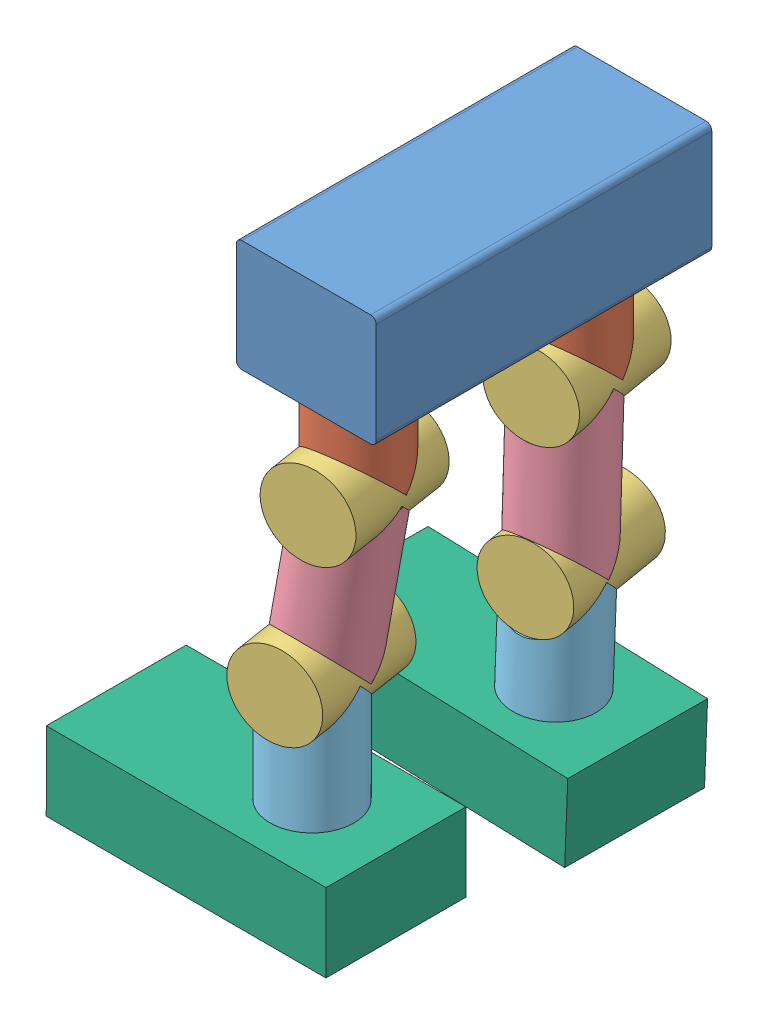
SolidWorks assembly Assem2, configuration Default. Lengths in mm.
Overall size (536.28 1007.15 671.91).
13 component instances, 6 part files, 12 mates.
Components (placement in the parent):
- base robot 1-1: base robot 1 [Default] at (242.1408 347.3277 425.7368) x (-1 0 0) z (0 0 -1) size (250 200 600)
- Part3-1: Part3 [Default] at (115.1155 194.7387 638.1636) x (0.155021 0 0.987911) z (0 1 0) size (150 150 150)
- Part3-2: Part3 [Default] at (119.2139 183.9077 256.4467) x (0.167393 0 0.98589) z (0 1 0) size (150 150 150)
- circle-1: circle [Default] at (103.4318 183.9077 146.1748) x (-0.34025 0.938559 0.057771) z (0.167393 0 0.98589) size (150 150 200)
- circle-2: circle [Default] at (102.9103 194.7387 541.6802) x (0.673179 -0.731896 -0.105634) z (0.155021 0 0.987911) size (150 150 200)
- Part2-1: Part2 [Default] at (123.2154 33.8869 269.867) x (0.985545 -0.026462 -0.167334) z (-0.026088 -0.99965 0.00443) size (150 150 300)
- Part2-2: Part2 [Default] at (97.2992 46.2421 643.7397) x (0.975079 -0.160654 -0.153008) z (0.158712 0.987011 -0.024905) size (150 150 300)
- circle-3: circle [Default] at (56.0986 -101.3646 554.2624) x (-0.421517 -0.904405 0.066144) z (0.155021 0 0.987911) size (150 150 200)
- circle-4: circle [Default] at (95.8401 -115.9873 148.8872) x (0.975769 -0.142923 -0.165674) z (0.167393 0 0.98589) size (150 150 200)
- Part4-1: Part4 [Default] at (113.4697 -240.9143 278.2366) x (0.985314 -0.034171 -0.167295) z (0.033689 0.999416 -0.00572) size (150 150 250)
- Part4-2: Part4 [Default] at (74.86 -226.3645 674.7068) x (0.987911 -0.001095 -0.155021) z (0.001082 0.999999 -0.00017) size (150 150 250)
- foot-3: foot [Default] at (12.7478 -310.835 276.5564) x (-0.999432 0.033689 -0.000096) z (-0.000096 -0.00572 -0.999984) size (500 140 250)
- foot-4: foot [Default] at (-23.5105 -307.1578 672.6264) x (-0.999999 0.001082 0) z (0 -0.00017 -1) size (500 140 250)
Mates (geometry in assembly coordinates):
- Concentric30: concentric aligned: cylinder of base robot 1-1 through (121.1663 397.3277 250.6257) axis (0 -1 0) radius 75; cylinder of Part3-2 through (121.1663 333.9077 250.6257) axis (0 -1 0) radius 75
- Concentric31: concentric anti-aligned: cylinder of Part3-2 through (107.8439 183.9077 172.1607) axis (0.167393 0 0.98589) radius 75; cylinder of circle-1 through (136.9104 183.9077 343.3529) axis (-0.167393 0 -0.98589) radius 75
- Concentric32: concentric anti-aligned: cylinder of Part3-1 through (104.803 194.7387 553.7417) axis (0.155021 0 0.987911) radius 75; cylinder of circle-2 through (133.9146 194.7387 739.2624) axis (-0.155021 0 -0.987911) radius 75
- Concentric33: concentric anti-aligned: cylinder of Part2-1 through (104.0182 -115.9873 197.0531) axis (0.167393 0 0.98589) radius 75; cylinder of circle-4 through (129.3187 -115.9873 346.0652) axis (-0.167393 0 -0.98589) radius 75
- Concentric34: concentric aligned: cylinder of Part2-2 through (82.4186 -101.3646 721.9925) axis (-0.155021 0 -0.987911) radius 75; cylinder of circle-3 through (87.1029 -101.3646 751.8446) axis (-0.155021 0 -0.987911) radius 75
- Concentric36: concentric aligned: cylinder of circle-2 through (133.9146 194.7387 739.2624) axis (-0.155021 0 -0.987911) radius 75; cylinder of Part2-2 through (130.0322 194.7387 714.521) axis (-0.155021 0 -0.987911) radius 75
- Concentric37: concentric aligned: cylinder of base robot 1-1 through (117.1408 397.3277 632.3676) axis (0 -1 0) radius 75; cylinder of Part3-1 through (117.1408 344.7387 632.3676) axis (0 -1 0) radius 75
- Concentric44: concentric anti-aligned: cylinder of circle-1 through (136.9104 183.9077 343.3529) axis (-0.167393 0 -0.98589) radius 75; cylinder of Part2-1 through (111.8447 183.9077 195.7242) axis (0.167393 0 0.98589) radius 75
- Concentric45: concentric aligned: cylinder of circle-4 through (129.3187 -115.9873 346.0652) axis (-0.167393 0 -0.98589) radius 75; cylinder of Part4-1 through (134.4201 -115.9873 376.1107) axis (-0.167393 0 -0.98589) radius 75
- Concentric46: concentric aligned: cylinder of circle-3 through (87.1029 -101.3646 751.8446) axis (-0.155021 0 -0.987911) radius 75; cylinder of Part4-2 through (90.4974 -101.3646 773.4767) axis (-0.155021 0 -0.987911) radius 75
- Concentric47: concentric aligned: circle of Part4-1; cylinder of foot-3 through (107.2777 -414.0766 277.1379) axis (0.033689 0.999416 -0.00572) radius 75
- Concentric48: concentric aligned: circle of Part4-2; circle of foot-4
